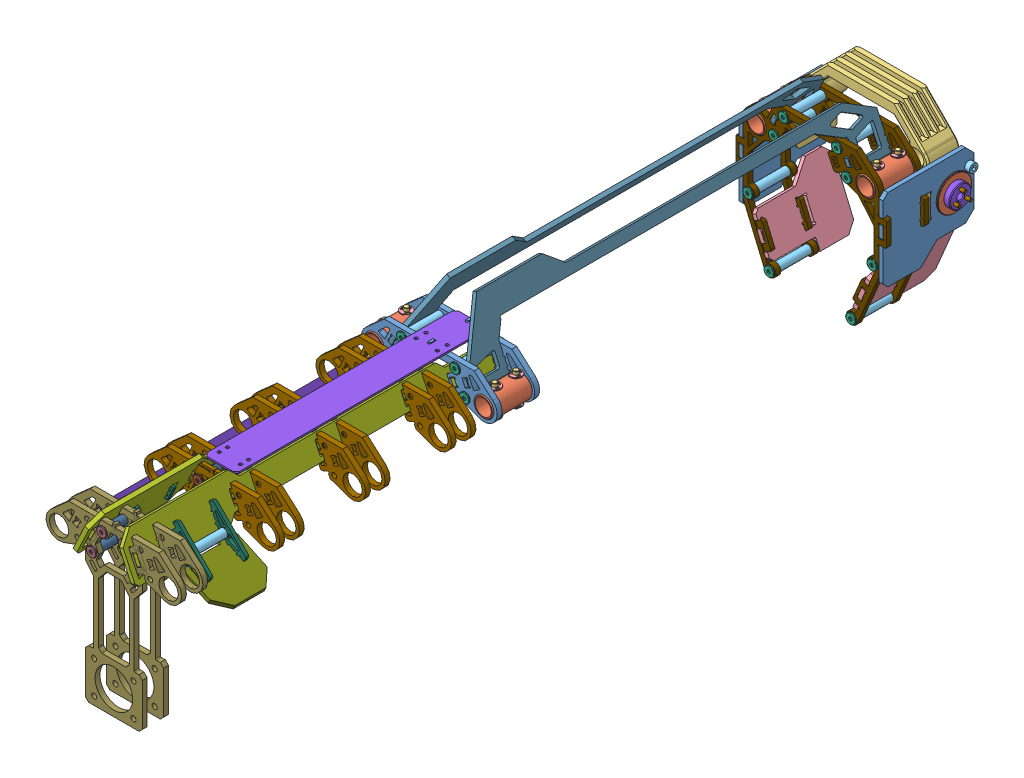
SolidWorks assembly 弹轮后支撑装配, configuration 默认. Lengths in mm.
Overall size (130 173.61 489.15).
144 component instances, 27 part files, 139 mates.
Components (placement in the parent):
- 弹轮后支撑-轨道连接板_3mm-1: 弹轮后支撑-轨道连接板_3mm [默认] at (0 0 -11.5) size (83 25.5 3)
- 碳管垫套_装填用_直径10mm-1: 碳管垫套_装填用_直径10mm [默认] at (33.5 0 0) x (0 1 0) z (0 0 1) size (14 14 27)
- 弹轮后支撑-轨道连接板_3mm-2: 弹轮后支撑-轨道连接板_3mm [默认] at (0 0 11.5) size (83 25.5 3)
- 碳管垫套_装填用_直径10mm-2: 碳管垫套_装填用_直径10mm [默认] at (-33.5 0 0) x (0 -1 0) z (0 0 1) size (14 14 27)
- M3×20卡簧销（工作长度15）-1: M3×20卡簧销（工作长度15） [默认] at (-33.5 0 6.5) x (0 -1 0) z (0.546944 0 -0.837169) size (20 3 3)
- M3×20卡簧销（工作长度15）-2: M3×20卡簧销（工作长度15） [默认] at (-33.5 0 -6.5) x (0 -1 0) z (0.546944 0 -0.837169) size (20 3 3)
- M3卡簧-1: M3卡簧 [默认] at (-33.5 8.1 6.5) x (-0.546944 0 0.837169) z (0 -1 0) size (7 6.39 0.6)
- M3卡簧-2: M3卡簧 [默认] at (-33.5 -7.5 -6.5) x (-0.546944 0 0.837169) z (0 -1 0) size (7 6.39 0.6)
- M3卡簧-3: M3卡簧 [默认] at (-33.5 8.1 -6.5) x (-0.546944 0 0.837169) z (0 -1 0) size (7 6.39 0.6)
- M3卡簧-4: M3卡簧 [默认] at (-33.5 -7.5 6.5) x (-0.546944 0 0.837169) z (0 -1 0) size (7 6.39 0.6)
- M3卡簧-5: M3卡簧 [默认] at (33.5 7.5 6.5) x (0.546944 0 0.837169) z (0 1 0) size (7 6.39 0.6)
- M3×20卡簧销（工作长度15）-3: M3×20卡簧销（工作长度15） [默认] at (33.5 0 6.5) x (0 -1 0) z (0.546944 0 0.837169) size (20 3 3)
- M3卡簧-6: M3卡簧 [默认] at (33.5 7.5 -6.5) x (0.546944 0 0.837169) z (0 1 0) size (7 6.39 0.6)
- M3×20卡簧销（工作长度15）-4: M3×20卡簧销（工作长度15） [默认] at (33.5 0 -6.5) x (0 -1 0) z (0.546944 0 0.837169) size (20 3 3)
- M3卡簧-7: M3卡簧 [默认] at (33.5 -8.1 -6.5) x (0.546944 0 0.837169) z (0 1 0) size (7 6.39 0.6)
- M3卡簧-8: M3卡簧 [默认] at (33.5 -8.1 6.5) x (0.546944 0 0.837169) z (0 1 0) size (7 6.39 0.6)
- M3×Φ5×20-1: M3×Φ5×20 [默认] at (-22.2445 -0.6154 0) size (5 5 20)
- M3×Φ5×20-2: M3×Φ5×20 [默认] at (-16.3278 12.0729 0) x (0.998279 0.058649 0) z (0 0 1) size (5 5 20)
- M3×8扁头螺丝-1: M3×8扁头螺丝 [默认] at (-16.3278 12.0729 13.5) size (6 6 9)
- M3×8扁头螺丝-2: M3×8扁头螺丝 [默认] at (-22.2445 -0.6154 13.5) size (6 6 9)
- M3×Φ5×20-3: M3×Φ5×20 [默认] at (16.3278 12.0729 0) x (-0.998279 0.058649 0) z (0 0 -1) size (5 5 20)
- M3×Φ5×20-4: M3×Φ5×20 [默认] at (22.2445 -0.6154 0) x (-1 0 0) z (0 0 -1) size (5 5 20)
- M3×8扁头螺丝-3: M3×8扁头螺丝 [默认] at (16.3278 12.0729 13.5) size (6 6 9)
- M3×8扁头螺丝-4: M3×8扁头螺丝 [默认] at (22.2445 -0.6154 13.5) size (6 6 9)
- M3×8扁头螺丝-5: M3×8扁头螺丝 [默认] at (-16.3278 12.0729 -13.5) x (0.592462 0.805599 0) z (0 0 -1) size (6 6 9)
- M3×8扁头螺丝-6: M3×8扁头螺丝 [默认] at (-22.2445 -0.6154 -13.5) x (0.639071 0.769148 0) z (0 0 -1) size (6 6 9)
- M3×8扁头螺丝-7: M3×8扁头螺丝 [默认] at (16.3278 12.0729 -13.5) x (0.592462 -0.805599 0) z (0 0 -1) size (6 6 9)
- M3×8扁头螺丝-8: M3×8扁头螺丝 [默认] at (22.2445 -0.6154 -13.5) x (0.639071 -0.769148 0) z (0 0 -1) size (6 6 9)
- 弹轮后支撑梁板_2.5mm-1: 弹轮后支撑梁板_2.5mm [默认] at (-14.9812 3.7213 96.4) x (0 0 1) z (-0.906308 0.422618 0) size (231 26 2.5)
- 弹轮后固定装饰板_1mm-1: 弹轮后固定装饰板_1mm [默认] at (0 16.5 64) x (0 0 1) z (0 -1 0) size (154 20 1)
- 弹轮后支撑梁板加强板_2mm-1: 弹轮后支撑梁板加强板_2mm [默认] at (0 -1.1831 27.4) size (83 25.5 3)
- 弹轮后支撑梁板加强板_2mm-2: 弹轮后支撑梁板加强板_2mm [默认] at (0 -1.1831 39.4) size (83 25.5 3)
- M3×Φ5×10-1: M3×Φ5×10 [默认] at (8.4109 6.572 33.4) size (5 5 10)
- M3×5扁头螺丝-1: M3×5扁头螺丝 [默认] at (8.4109 6.572 25.9) x (0.791441 0.611246 0) z (0 0 -1) size (6 6 6)
- M3×5扁头螺丝-2: M3×5扁头螺丝 [默认] at (8.4109 6.572 40.9) size (6 6 6)
- M3×Φ5×10-2: M3×Φ5×10 [默认] at (-8.4109 6.572 33.4) x (-1 0 0) z (0 0 -1) size (5 5 10)
- M3×5扁头螺丝-3: M3×5扁头螺丝 [默认] at (-8.4109 6.572 25.9) x (0.791441 -0.611246 0) z (0 0 -1) size (6 6 6)
- M3×5扁头螺丝-4: M3×5扁头螺丝 [默认] at (-8.4109 6.572 40.9) size (6 6 6)
- 弹轮后支撑梁板加强板_2mm-3: 弹轮后支撑梁板加强板_2mm [默认] at (0 -1.1831 91.9) size (83 25.5 3)
- 弹轮后支撑梁板加强板_2mm-4: 弹轮后支撑梁板加强板_2mm [默认] at (0 -1.1831 144.4) size (83 25.5 3)
- 弹轮后支撑梁板加强板_2mm-5: 弹轮后支撑梁板加强板_2mm [默认] at (0 -1.1831 79.9) size (83 25.5 3)
- 弹轮后支撑梁板加强板_2mm-6: 弹轮后支撑梁板加强板_2mm [默认] at (0 -1.1831 132.4) size (83 25.5 3)
- M3×5扁头螺丝-5: M3×5扁头螺丝 [默认] at (-8.4109 6.572 78.4) x (0.791441 -0.611246 0) z (0 0 -1) size (6 6 6)
- M3×5扁头螺丝-6: M3×5扁头螺丝 [默认] at (-8.4109 6.572 130.9) x (0.791441 -0.611246 0) z (0 0 -1) size (6 6 6)
- M3×5扁头螺丝-7: M3×5扁头螺丝 [默认] at (-8.4109 6.572 93.4) size (6 6 6)
- M3×5扁头螺丝-8: M3×5扁头螺丝 [默认] at (-8.4109 6.572 145.9) size (6 6 6)
- M3×Φ5×10-3: M3×Φ5×10 [默认] at (-8.4109 6.572 85.9) x (-1 0 0) z (0 0 -1) size (5 5 10)
- M3×Φ5×10-4: M3×Φ5×10 [默认] at (-8.4109 6.572 138.4) x (-1 0 0) z (0 0 -1) size (5 5 10)
- M3×5扁头螺丝-9: M3×5扁头螺丝 [默认] at (8.4109 6.572 93.4) size (6 6 6)
- M3×5扁头螺丝-10: M3×5扁头螺丝 [默认] at (8.4109 6.572 145.9) size (6 6 6)
- M3×5扁头螺丝-11: M3×5扁头螺丝 [默认] at (8.4109 6.572 78.4) x (0.791441 0.611246 0) z (0 0 -1) size (6 6 6)
- M3×5扁头螺丝-12: M3×5扁头螺丝 [默认] at (8.4109 6.572 130.9) x (0.791441 0.611246 0) z (0 0 -1) size (6 6 6)
- M3×Φ5×10-5: M3×Φ5×10 [默认] at (8.4109 6.572 85.9) size (5 5 10)
- M3×Φ5×10-6: M3×Φ5×10 [默认] at (8.4109 6.572 138.4) size (5 5 10)
- 弹轮后支撑托垫板_3mm-1: 弹轮后支撑托垫板_3mm [默认] at (0 0 191.4) size (83 102 3)
- 弹轮后支撑托垫板_3mm-2: 弹轮后支撑托垫板_3mm [默认] at (0 0 204.4) size (83 102 3)
- M3×6扁头螺丝-1: M3×6扁头螺丝 [默认] at (-13.0006 -3.2708 206.4) size (6 6 7)
- M3×6扁头螺丝-2: M3×6扁头螺丝 [默认] at (-6.6614 10.3238 206.4) size (6 6 7)
- M3×6扁头螺丝-3: M3×6扁头螺丝 [默认] at (-6.6614 10.3238 189.4) x (-0.778141 0.62809 0) z (0 0 -1) size (6 6 7)
- M3×6扁头螺丝-4: M3×6扁头螺丝 [默认] at (-13.0006 -3.2708 189.4) x (-0.791739 0.61086 0) z (0 0 -1) size (6 6 7)
- M3×6扁头螺丝-5: M3×6扁头螺丝 [默认] at (13.0006 -3.2708 189.4) x (-0.791739 -0.61086 0) z (0 0 -1) size (6 6 7)
- M3×6扁头螺丝-6: M3×6扁头螺丝 [默认] at (13.0006 -3.2708 206.4) size (6 6 7)
- M3×6扁头螺丝-7: M3×6扁头螺丝 [默认] at (6.6614 10.3238 206.4) size (6 6 7)
- M3×6扁头螺丝-8: M3×6扁头螺丝 [默认] at (6.6614 10.3238 189.4) x (-0.778141 -0.62809 0) z (0 0 -1) size (6 6 7)
- 弹轮后支撑梁板_2.5mm-3: 弹轮后支撑梁板_2.5mm [默认] at (14.9812 3.7213 96.4) x (0 0 1) z (-0.906308 -0.422618 0) size (231 26 2.5)
- M3×Φ5×10-11: M3×Φ5×10 [默认] at (-6.6614 10.3238 197.9) x (0.722592 0.691274 0) z (0 0 1) size (5 5 10)
- M3×Φ5×10-12: M3×Φ5×10 [默认] at (-13.0006 -3.2708 197.9) x (0.999082 -0.042836 0) z (0 0 1) size (5 5 10)
- M3×Φ5×10-13: M3×Φ5×10 [默认] at (6.6614 10.3238 197.9) x (-0.722592 0.691274 0) z (0 0 -1) size (5 5 10)
- M3×Φ5×10-14: M3×Φ5×10 [默认] at (13.0006 -3.2708 197.9) x (-0.999082 -0.042836 0) z (0 0 -1) size (5 5 10)
- M3卡簧-9: M3卡簧 [默认] at (33.5 -8.1 -240) x (0.546944 0 0.837169) z (0 1 0) size (7 6.39 0.6)
- M3卡簧-10: M3卡簧 [默认] at (33.5 -8.1 -227) x (0.546944 0 0.837169) z (0 1 0) size (7 6.39 0.6)
- M3×Φ5×20-5: M3×Φ5×20 [默认] at (22.2445 -0.6154 -233.5) x (-1 0 0) z (0 0 -1) size (5 5 20)
- M3卡簧-11: M3卡簧 [默认] at (33.5 7.5 -227) x (0.546944 0 0.837169) z (0 1 0) size (7 6.39 0.6)
- M3卡簧-12: M3卡簧 [默认] at (33.5 7.5 -240) x (0.546944 0 0.837169) z (0 1 0) size (7 6.39 0.6)
- M3×20卡簧销（工作长度15）-5: M3×20卡簧销（工作长度15） [默认] at (33.5 0 -240) x (0 -1 0) z (0.546944 0 0.837169) size (20 3 3)
- M3×20卡簧销（工作长度15）-6: M3×20卡簧销（工作长度15） [默认] at (33.5 0 -227) x (0 -1 0) z (0.546944 0 0.837169) size (20 3 3)
- 碳管垫套_装填用_直径10mm-3: 碳管垫套_装填用_直径10mm [默认] at (33.5 0 -233.5) x (0 1 0) z (0 0 1) size (14 14 27)
- M3×8扁头螺丝-9: M3×8扁头螺丝 [默认] at (22.2445 -0.6154 -220) size (6 6 9)
- M3×8扁头螺丝-10: M3×8扁头螺丝 [默认] at (16.3278 12.0729 -220) size (6 6 9)
- M3×Φ5×20-6: M3×Φ5×20 [默认] at (16.3278 12.0729 -233.5) x (-0.998279 0.058649 0) z (0 0 -1) size (5 5 20)
- M3×8扁头螺丝-11: M3×8扁头螺丝 [默认] at (16.3278 12.0729 -247) x (0.592462 -0.805599 0) z (0 0 -1) size (6 6 9)
- M3×8扁头螺丝-12: M3×8扁头螺丝 [默认] at (22.2445 -0.6154 -247) x (0.639071 -0.769148 0) z (0 0 -1) size (6 6 9)
- M3×8扁头螺丝-13: M3×8扁头螺丝 [默认] at (-22.2445 -0.6154 -247) x (0.639071 0.769148 0) z (0 0 -1) size (6 6 9)
- M3×8扁头螺丝-14: M3×8扁头螺丝 [默认] at (-16.3278 12.0729 -247) x (0.592462 0.805599 0) z (0 0 -1) size (6 6 9)
- M3×8扁头螺丝-15: M3×8扁头螺丝 [默认] at (-22.2445 -0.6154 -220) size (6 6 9)
- M3×8扁头螺丝-16: M3×8扁头螺丝 [默认] at (-16.3278 12.0729 -220) size (6 6 9)
- M3×Φ5×20-7: M3×Φ5×20 [默认] at (-22.2445 -0.6154 -233.5) size (5 5 20)
- M3×Φ5×20-8: M3×Φ5×20 [默认] at (-16.3278 12.0729 -233.5) x (0.998279 0.058649 0) z (0 0 1) size (5 5 20)
- M3卡簧-13: M3卡簧 [默认] at (-33.5 8.1 -227) x (-0.546944 0 0.837169) z (0 -1 0) size (7 6.39 0.6)
- M3×20卡簧销（工作长度15）-7: M3×20卡簧销（工作长度15） [默认] at (-33.5 0 -227) x (0 -1 0) z (0.546944 0 -0.837169) size (20 3 3)
- M3卡簧-14: M3卡簧 [默认] at (-33.5 -7.5 -227) x (-0.546944 0 0.837169) z (0 -1 0) size (7 6.39 0.6)
- M3卡簧-15: M3卡簧 [默认] at (-33.5 -7.5 -240) x (-0.546944 0 0.837169) z (0 -1 0) size (7 6.39 0.6)
- M3×20卡簧销（工作长度15）-8: M3×20卡簧销（工作长度15） [默认] at (-33.5 0 -240) x (0 -1 0) z (0.546944 0 -0.837169) size (20 3 3)
- M3卡簧-16: M3卡簧 [默认] at (-33.5 8.1 -240) x (-0.546944 0 0.837169) z (0 -1 0) size (7 6.39 0.6)
- 碳管垫套_装填用_直径10mm-4: 碳管垫套_装填用_直径10mm [默认] at (-33.5 0 -233.5) x (0 -1 0) z (0 0 1) size (14 14 27)
- 轨道上支撑梁板_2.5mm-1: 轨道上支撑梁板_2.5mm [默认] at (-25.0092 2.3288 -116.75) x (0 0 1) z (-0.906308 0.422618 0) size (260.5 40 2.5)
- 轨道上支撑梁板_2.5mm-3: 轨道上支撑梁板_2.5mm [默认] at (25.0092 2.3288 -116.75) x (0 0 1) z (-0.906308 -0.422618 0) size (260.5 40 2.5)
- 弹轮后支撑梁板装饰板支撑板_2mm-1: 弹轮后支撑梁板装饰板支撑板_2mm [默认] at (-21.1574 0.5327 158.9) x (0.906308 0.422618 0) z (0 0 1) size (28.49 16.46 2)
- 弹轮后支撑梁板装饰板支撑板_2mm-2: 弹轮后支撑梁板装饰板支撑板_2mm [默认] at (-21.1574 0.5327 180.9) x (0.906308 0.422618 0) z (0 0 1) size (28.49 16.46 2)
- M3×Φ5×20-9: M3×Φ5×20 [默认] at (-21.1574 0.5327 169.9) size (5 5 20)
- M3×6扁头螺丝-9: M3×6扁头螺丝 [默认] at (-21.1574 0.5327 157.4) x (-0.923728 -0.383049 0) z (0 0 -1) size (6 6 7)
- M3×6扁头螺丝-10: M3×6扁头螺丝 [默认] at (-21.1574 0.5327 182.4) size (6 6 7)
- M3×Φ5×20-10: M3×Φ5×20 [默认] at (21.1574 0.5327 169.9) x (-1 0 0) z (0 0 -1) size (5 5 20)
- 弹轮后支撑梁板装饰板支撑板_2mm-3: 弹轮后支撑梁板装饰板支撑板_2mm [默认] at (21.1574 0.5327 158.9) x (-0.906308 0.422618 0) z (0 0 -1) size (28.49 16.46 2)
- 弹轮后支撑梁板装饰板支撑板_2mm-4: 弹轮后支撑梁板装饰板支撑板_2mm [默认] at (21.1574 0.5327 180.9) x (-0.906308 0.422618 0) z (0 0 -1) size (28.49 16.46 2)
- M3×6扁头螺丝-11: M3×6扁头螺丝 [默认] at (21.1574 0.5327 182.4) size (6 6 7)
- M3×6扁头螺丝-12: M3×6扁头螺丝 [默认] at (21.1574 0.5327 157.4) x (-0.923728 0.383049 0) z (0 0 -1) size (6 6 7)
- 弹轮后固定装饰板2_2.5mm-4: 弹轮后固定装饰板2_2.5mm [默认] at (19.8144 -3.5304 169.9) x (0 0 -1) z (0.422618 0.906308 0) size (35 30 2.5)
- 弹轮后固定装饰板3_2.5mm-5: 弹轮后固定装饰板3_2.5mm [默认] at (-19.8144 -3.5304 100.7) x (0 0 -1) z (0.422618 -0.906308 0) size (173.4 30 2.5)
- 飞镖架前支撑-轨道连接板_3mm-1: 飞镖架前支撑-轨道连接板_3mm [默认] at (0 0 -245) x (-1 0 0) z (0 0 -1) size (92 93.5 3)
- 飞镖架前支撑-轨道连接板_3mm-2: 飞镖架前支撑-轨道连接板_3mm [默认] at (0 0 -222) x (-1 0 0) z (0 0 -1) size (92 93.5 3)
- 飞镖架前支撑轴承板_2.5mm-1: 飞镖架前支撑轴承板_2.5mm [默认] at (42.75 -19.5 -233.5) x (0 0 -1) z (1 0 0) size (55.53 50 2.5)
- M3×8扁头螺丝-17: M3×8扁头螺丝 [默认] at (38 -39 -220) size (6 6 9)
- M3×8扁头螺丝-18: M3×8扁头螺丝 [默认] at (38 -39 -247) x (-0.877487 0.479601 0) z (0 0 -1) size (6 6 9)
- M3×Φ5×20-11: M3×Φ5×20 [默认] at (38 -39 -233.5) size (5 5 20)
- 飞镖架前支撑轴承板_2.5mm-2: 飞镖架前支撑轴承板_2.5mm [默认] at (-42.75 -19.5 -233.5) x (0 0 -1) z (1 0 0) size (55.53 50 2.5)
- M3×8扁头螺丝-19: M3×8扁头螺丝 [默认] at (-38 -39 -247) x (-0.877487 -0.479601 0) z (0 0 -1) size (6 6 9)
- M3×Φ5×20-12: M3×Φ5×20 [默认] at (-38 -39 -233.5) x (-1 0 0) z (0 0 -1) size (5 5 20)
- M3×8扁头螺丝-20: M3×8扁头螺丝 [默认] at (-38 -39 -220) size (6 6 9)
- 法兰轴承10×19×5-1: 法兰轴承10×19×5 [默认] at (-45 -19.5 -263.5) x (0 -0.388043 -0.921641) z (1 0 0) size (21 21 5)
- 飞镖架前支撑轴承垫块-1: 飞镖架前支撑轴承垫块 [默认] at (0 0 -263.5) size (88 54.76 29.5)
- 法兰轴承10×19×5-2: 法兰轴承10×19×5 [默认] at (45 -19.5 -263.5) x (0 0.388043 0.921641) z (-1 0 0) size (21 21 5)
- 飞镖架前支撑装饰板_2.5mm-1: 飞镖架前支撑装饰板_2.5mm [默认] at (30.7414 -58.5129 -245.5) x (0 0 -1) z (-0.389823 -0.92089 0) size (50.02 2.5 35)
- 飞镖架前支撑装饰板_2.5mm-2: 飞镖架前支撑装饰板_2.5mm [默认] at (-30.7414 -58.5129 -245.5) x (0 0 -1) z (0.389823 -0.92089 0) size (50.02 2.5 35)
- M3×8扁头螺丝-21: M3×8扁头螺丝 [默认] at (25 -74 -220) x (-0.75335 0.65762 0) z (0 0 1) size (6 6 9)
- M3×8扁头螺丝-22: M3×8扁头螺丝 [默认] at (25 -74 -247) x (-0.440843 -0.897584 0) z (0 0 -1) size (6 6 9)
- M3×Φ5×20-13: M3×Φ5×20 [默认] at (25 -74 -233.5) size (5 5 20)
- M3×Φ5×20-14: M3×Φ5×20 [默认] at (-25 -74 -233.5) x (-1 0 0) z (0 0 -1) size (5 5 20)
- M3×8扁头螺丝-23: M3×8扁头螺丝 [默认] at (-25 -74 -247) x (-0.440843 0.897584 0) z (0 0 -1) size (6 6 9)
- M3×8扁头螺丝-24: M3×8扁头螺丝 [默认] at (-25 -74 -220) x (-0.75335 -0.65762 0) z (0 0 1) size (6 6 9)
- 内六角圆柱头螺钉M3×10-1: 内六角圆柱头螺钉M3×10 [默认] at (47 -9.9541 -273.0459) x (-1 0 0) z (0 0.999499 -0.031662) size (13 5.2 5.2)
- M3防松-2: M3防松 [默认] at (38.1 -9.9541 -273.0459) x (0 -0.142302 -0.989823) z (0 0.989823 -0.142302) size (6.24 3.5 5.4)
- 内六角圆柱头螺钉M3×10-3: 内六角圆柱头螺钉M3×10 [默认] at (-47 -9.9541 -273.0459) x (1 0 0) z (0 -0.999499 0.031662) size (13 5.2 5.2)
- M3防松-3: M3防松 [默认] at (-38.1 -9.9541 -273.0459) x (0 -0.142302 -0.989823) z (0 -0.989823 0.142302) size (6.24 3.5 5.4)
- 飞镖架前支撑轴系垫块1-1: 飞镖架前支撑轴系垫块1 [默认] at (-40 -19.5 -263.5) x (0 0.853684 -0.520791) z (1 0 0) size (13.5 13.5 5.06)
- 飞镖架前支撑轴系垫块2-1: 飞镖架前支撑轴系垫块2 [默认] at (-45 -19.5 -263.5) x (0 0.024176 0.999708) z (-1 0 0) size (13.5 13.5 6.46)
- M2×6销钉-1: M2×6销钉 [默认] at (-48.5 -21.4157 -259.9886) x (0 -0.583122 0.812385) z (-1 0 0) size (2 2 6)
- M2×6销钉-2: M2×6销钉 [默认] at (-48.5 -15.5012 -263.5967) x (0 -0.912857 0.408278) z (-1 0 0) size (2 2 6)
- M2×6销钉-3: M2×6销钉 [默认] at (-48.5 -21.5832 -266.9147) x (0 -0.993447 0.114292) z (-1 0 0) size (2 2 6)
- 飞镖架前支撑轴系垫块2-2: 飞镖架前支撑轴系垫块2 [默认] at (45 -19.5 -263.5) x (0 -0.024176 -0.999708) z (1 0 0) size (13.5 13.5 6.46)
- M2×6销钉-4: M2×6销钉 [默认] at (48.5 -15.5012 -263.5967) x (0 -0.912857 0.408278) z (-1 0 0) size (2 2 6)
- M2×6销钉-5: M2×6销钉 [默认] at (48.5 -21.4157 -259.9886) x (0 -0.583122 0.812385) z (-1 0 0) size (2 2 6)
- M2×6销钉-6: M2×6销钉 [默认] at (48.5 -21.5832 -266.9147) x (0 -0.993447 0.114292) z (-1 0 0) size (2 2 6)
- 飞镖架前支撑轴系垫块1-2: 飞镖架前支撑轴系垫块1 [默认] at (40 -19.5 -263.5) x (0 -0.853684 0.520791) z (-1 0 0) size (13.5 13.5 5.06)
Mates (geometry in assembly coordinates):
- 重合2: coincident aligned: plane of 弹轮后支撑-轨道连接板_3mm-1 through (0 0 -11.5) normal (0 1 0)
- 重合3: coincident aligned: plane of 弹轮后支撑-轨道连接板_3mm-1 through (0 0 -11.5) normal (1 0 0)
- 同心1: concentric anti-aligned: cylinder of 弹轮后支撑-轨道连接板_3mm-1 through (33.5 0 -10) axis (0 0 -1) radius 6; cylinder of 碳管垫套_装填用_直径10mm-1 through (33.5 0 13.5) axis (0 0 1) radius 6.05
- 重合4: coincident anti-aligned: plane of 弹轮后支撑-轨道连接板_3mm-1 through (-33.5 0 -10) normal (0 0 1); plane of 碳管垫套_装填用_直径10mm-1 through (27.45 0 -10) normal (0 0 -1)
- 同心2: concentric anti-aligned: cylinder of 碳管垫套_装填用_直径10mm-1 through (33.5 0 13.5) axis (0 0 1) radius 6.05; cylinder of 弹轮后支撑-轨道连接板_3mm-2 through (33.5 0 13) axis (0 0 -1) radius 6
- 重合5: coincident anti-aligned: plane of 碳管垫套_装填用_直径10mm-1 through (26.5 0 10) normal (0 0 1); plane of 弹轮后支撑-轨道连接板_3mm-2 through (-33.5 0 10) normal (0 0 -1)
- 同心3: concentric aligned: cylinder of 弹轮后支撑-轨道连接板_3mm-1 through (-33.5 0 -10) axis (0 0 -1) radius 6; cylinder of 弹轮后支撑-轨道连接板_3mm-2 through (-33.5 0 13) axis (0 0 -1) radius 6
- 同心4: concentric anti-aligned: cylinder of 弹轮后支撑-轨道连接板_3mm-2 through (-33.5 0 13) axis (0 0 -1) radius 6; cylinder of 碳管垫套_装填用_直径10mm-2 through (-33.5 0 13.5) axis (0 0 1) radius 6.05
- 重合6: coincident anti-aligned: plane of 弹轮后支撑-轨道连接板_3mm-2 through (-33.5 0 10) normal (0 0 -1); plane of 碳管垫套_装填用_直径10mm-2 through (-26.5 0 10) normal (0 0 1)
- 对称2: symmetric aligned: plane of 弹轮后支撑-轨道连接板_3mm-1 through (-33.5 0 -10) normal (0 0 1); plane of 弹轮后支撑-轨道连接板_3mm-2 through (-33.5 0 10) normal (0 0 -1)
- 同心5: concentric anti-aligned: cylinder of M3×20卡簧销（工作长度15）-1 through (-33.5 8.1 6.5) axis (0 -1 0) radius 1.2; cylinder of M3卡簧-1 through (-33.5 7.5 6.5) axis (0 1 0) radius 1.4
- 重合7: coincident anti-aligned: plane of M3×20卡簧销（工作长度15）-1 through (-33.5 8.1 6.5) normal (0 -1 0); plane of M3卡簧-1 through (-33.5 8.1 6.5) normal (0 1 0)
- 同心6: concentric aligned: cylinder of M3×20卡簧销（工作长度15）-1 through (-33.5 -8.1 6.5) axis (0 1 0) radius 1.2; cylinder of M3卡簧-4 through (-33.5 -8.1 6.5) axis (0 1 0) radius 1.4
- 重合8: coincident anti-aligned: plane of M3×20卡簧销（工作长度15）-1 through (-33.5 -8.1 6.5) normal (0 1 0); plane of M3卡簧-4 through (-33.5 -8.1 6.5) normal (0 -1 0)
- 同心7: concentric anti-aligned: cylinder of 碳管垫套_装填用_直径10mm-2 through (-33.5 7 6.5) axis (0 -1 0) radius 1.45; cylinder of M3×20卡簧销（工作长度15）-1 through (-33.5 -10 6.5) axis (0 1 0) radius 1.5
- 重合9: coincident aligned: plane of 碳管垫套_装填用_直径10mm-2 through (-33.5 0 0) normal (0 -1 0); plane of M3×20卡簧销（工作长度15）-1 through (-33.5 0 6.5) normal (0 -1 0)
- 同心8: concentric anti-aligned: cylinder of M3×20卡簧销（工作长度15）-2 through (-33.5 8.1 -6.5) axis (0 -1 0) radius 1.2; cylinder of M3卡簧-3 through (-33.5 7.5 -6.5) axis (0 1 0) radius 1.4
- 重合10: coincident anti-aligned: plane of M3×20卡簧销（工作长度15）-2 through (-33.5 8.1 -6.5) normal (0 -1 0); plane of M3卡簧-3 through (-33.5 8.1 -6.5) normal (0 1 0)
- 重合11: coincident anti-aligned: plane of M3×20卡簧销（工作长度15）-2 through (-33.5 -8.1 -6.5) normal (0 1 0); plane of M3卡簧-2 through (-33.5 -8.1 -6.5) normal (0 -1 0)
- 同心9: concentric aligned: cylinder of M3×20卡簧销（工作长度15）-2 through (-33.5 -8.1 -6.5) axis (0 1 0) radius 1.2; cylinder of M3卡簧-2 through (-33.5 -8.1 -6.5) axis (0 1 0) radius 1.4
- 同心10: concentric anti-aligned: cylinder of 碳管垫套_装填用_直径10mm-2 through (-33.5 7 -6.5) axis (0 -1 0) radius 1.45; cylinder of M3×20卡簧销（工作长度15）-2 through (-33.5 -10 -6.5) axis (0 1 0) radius 1.5
- 重合12: coincident aligned: plane of 碳管垫套_装填用_直径10mm-2 through (-33.5 0 0) normal (0 -1 0); plane of M3×20卡簧销（工作长度15）-2 through (-33.5 0 -6.5) normal (0 -1 0)
- 同心11: concentric anti-aligned: cylinder of 弹轮后支撑-轨道连接板_3mm-2 through (-16.3278 12.0729 10) axis (0 0 1) radius 1.55; cylinder of M3×Φ5×20-2 through (-16.3278 12.0729 10) axis (0 0 -1) radius 1.5
- 同心12: concentric anti-aligned: cylinder of 弹轮后支撑-轨道连接板_3mm-2 through (-22.2445 -0.6154 10) axis (0 0 1) radius 1.55; cylinder of M3×Φ5×20-1 through (-22.2445 -0.6154 10) axis (0 0 -1) radius 1.5
- 重合13: coincident anti-aligned: plane of 弹轮后支撑-轨道连接板_3mm-2 through (-33.5 0 10) normal (0 0 -1); plane of M3×Φ5×20-1 through (-22.2445 -0.6154 10) normal (0 0 1)
- 重合14: coincident anti-aligned: plane of 弹轮后支撑-轨道连接板_3mm-2 through (-33.5 0 10) normal (0 0 -1); plane of M3×Φ5×20-2 through (-16.3278 12.0729 10) normal (0 0 1)
- 同心13: concentric aligned: cylinder of 弹轮后支撑-轨道连接板_3mm-2 through (-16.3278 12.0729 10) axis (0 0 1) radius 1.55; cylinder of M3×8扁头螺丝-1 through (-16.3278 12.0729 5) axis (0 0 1) radius 1.5
- 同心14: concentric aligned: cylinder of 弹轮后支撑-轨道连接板_3mm-2 through (-22.2445 -0.6154 10) axis (0 0 1) radius 1.55; cylinder of M3×8扁头螺丝-2 through (-22.2445 -0.6154 5) axis (0 0 1) radius 1.5
- 重合15: coincident anti-aligned: plane of 弹轮后支撑-轨道连接板_3mm-2 through (-33.5 0 13) normal (0 0 1); plane of M3×8扁头螺丝-1 through (-16.3278 12.0729 13) normal (0 0 -1)
- 重合16: coincident anti-aligned: plane of 弹轮后支撑-轨道连接板_3mm-2 through (-33.5 0 13) normal (0 0 1); plane of M3×8扁头螺丝-2 through (-22.2445 -0.6154 13) normal (0 0 -1)
- 同心15: concentric anti-aligned: cylinder of 弹轮后支撑-轨道连接板_3mm-1 through (-16.3278 12.0729 -13) axis (0 0 1) radius 1.55; cylinder of M3×8扁头螺丝-5 through (-16.3278 12.0729 -5) axis (0 0 -1) radius 1.5
- 同心16: concentric anti-aligned: cylinder of 弹轮后支撑-轨道连接板_3mm-1 through (-22.2445 -0.6154 -13) axis (0 0 1) radius 1.55; cylinder of M3×8扁头螺丝-6 through (-22.2445 -0.6154 -5) axis (0 0 -1) radius 1.5
- 重合17: coincident anti-aligned: plane of 弹轮后支撑-轨道连接板_3mm-1 through (-33.5 0 -13) normal (0 0 -1); plane of M3×8扁头螺丝-5 through (-16.3278 12.0729 -13) normal (0 0 1)
- 重合18: coincident anti-aligned: plane of 弹轮后支撑-轨道连接板_3mm-1 through (-33.5 0 -13) normal (0 0 -1); plane of M3×8扁头螺丝-6 through (-22.2445 -0.6154 -13) normal (0 0 1)
- 重合19: coincident anti-aligned: plane of 弹轮后支撑-轨道连接板_3mm-2 through (-12.5 12 13) normal (0.906308 -0.422618 0); plane of 弹轮后支撑梁板_2.5mm-1 through (-16.1141 4.2496 96.4) normal (-0.906308 0.422618 0)
- 宽度1: width anti-aligned: plane of 弹轮后支撑梁板_2.5mm-1 through (-15.0575 6.5153 10.025) normal (0 0 1); plane of 弹轮后支撑梁板_2.5mm-1 through (-15.0575 6.5153 -10.025) normal (0 0 -1); plane of 弹轮后支撑-轨道连接板_3mm-2 through (-33.5 0 10) normal (0 0 -1); plane of 弹轮后支撑-轨道连接板_3mm-1 through (-33.5 0 -10) normal (0 0 1)
- 宽度2: width aligned: plane of 弹轮后支撑梁板_2.5mm-1 through (-15.0575 6.5153 10.025) normal (0.422618 0.906308 0); plane of 弹轮后支撑梁板_2.5mm-1 through (-17.1706 1.9838 13.025) normal (-0.422618 -0.906308 0); plane of 弹轮后支撑-轨道连接板_3mm-2 through (-14.9049 0.9272 10) normal (0.422618 0.906308 0); plane of 弹轮后支撑-轨道连接板_3mm-2 through (-15.0575 6.5153 10) normal (-0.422618 -0.906308 0)
- 重合20: coincident anti-aligned: plane of 弹轮后支撑-轨道连接板_3mm-1 through (-27.5 16 -10) normal (0 1 0); plane of 弹轮后固定装饰板_1mm-1 through (0 16 64) normal (0 -1 0)
- 重合21: coincident anti-aligned: plane of 弹轮后固定装饰板_1mm-1 through (0 16.5 64) normal (-1 0 0)
- 重合25: coincident anti-aligned: plane of 弹轮后支撑梁板_2.5mm-1 through (-13.8483 3.193 96.4) normal (0.906308 -0.422618 0); plane of 弹轮后支撑梁板加强板_2mm-1 through (-8.6246 14.3953 28.4) normal (-0.906308 0.422618 0)
- 重合27: coincident anti-aligned: plane of 弹轮后支撑梁板_2.5mm-1 through (-13.8483 3.193 96.4) normal (0.906308 -0.422618 0); plane of 弹轮后支撑梁板加强板_2mm-2 through (-8.6246 14.3953 40.4) normal (-0.906308 0.422618 0)
- 同心17: concentric anti-aligned: cylinder of 弹轮后支撑梁板加强板_2mm-2 through (8.4109 6.572 37.9) axis (0 0 1) radius 1.55; cylinder of M3×Φ5×10-1 through (8.4109 6.572 38.4) axis (0 0 -1) radius 1.5
- 重合29: coincident anti-aligned: plane of 弹轮后支撑梁板加强板_2mm-2 through (0 -1.1831 38.4) normal (0 0 -1); plane of M3×Φ5×10-1 through (8.4109 6.572 38.4) normal (0 0 1)
- 同心18: concentric aligned: cylinder of 弹轮后支撑梁板加强板_2mm-2 through (8.4109 6.572 37.9) axis (0 0 1) radius 1.55; cylinder of M3×5扁头螺丝-2 through (8.4109 6.572 35.4) axis (0 0 1) radius 1.5
- 重合30: coincident anti-aligned: plane of 弹轮后支撑梁板加强板_2mm-2 through (0 -1.1831 40.4) normal (0 0 1); plane of M3×5扁头螺丝-2 through (8.4109 6.572 40.4) normal (0 0 -1)
- 同心19: concentric anti-aligned: cylinder of 弹轮后支撑梁板加强板_2mm-1 through (8.4109 6.572 25.9) axis (0 0 1) radius 1.55; cylinder of M3×5扁头螺丝-1 through (8.4109 6.572 31.4) axis (0 0 -1) radius 1.5
- 重合31: coincident anti-aligned: plane of 弹轮后支撑梁板加强板_2mm-1 through (0 -1.1831 26.4) normal (0 0 -1); plane of M3×5扁头螺丝-1 through (8.4109 6.572 26.4) normal (0 0 1)
- 重合32: coincident anti-aligned: plane of 弹轮后支撑梁板加强板_2mm-1 through (0 -1.1831 28.4) normal (0 0 1); plane of M3×Φ5×10-1 through (8.4109 6.572 28.4) normal (0 0 -1)
- 重合33: coincident anti-aligned: plane of 弹轮后支撑梁板_2.5mm-1 through (-13.8483 3.193 96.4) normal (0.906308 -0.422618 0); plane of 弹轮后支撑托垫板_3mm-1 through (-8.5656 14.5219 192.9) normal (-0.906308 0.422618 0)
- 重合34: coincident anti-aligned: plane of 弹轮后支撑梁板_2.5mm-1 through (-13.8483 3.193 96.4) normal (0.906308 -0.422618 0); plane of 弹轮后支撑托垫板_3mm-2 through (-8.5656 14.5219 205.9) normal (-0.906308 0.422618 0)
- 宽度4: width anti-aligned: plane of 弹轮后支撑托垫板_3mm-1 through (0 0 192.9) normal (0 0 1); plane of 弹轮后支撑梁板_2.5mm-1 through (0 0 202.9) normal (0 0 -1); plane of 弹轮后支撑托垫板_3mm-2 through (-11.5239 8.1777 192.875) normal (0 0 -1); plane of 弹轮后支撑梁板_2.5mm-1 through (-11.5239 8.1777 202.925) normal (0 0 1)
- 重合37: coincident anti-aligned: plane of 弹轮后支撑托垫板_3mm-1 through (0 0 189.9) normal (0 0 -1); plane of M3×6扁头螺丝-4 through (-13.0006 -3.2708 189.9) normal (0 0 1)
- 重合38: coincident anti-aligned: plane of 弹轮后支撑托垫板_3mm-1 through (0 0 189.9) normal (0 0 -1); plane of M3×6扁头螺丝-3 through (-6.6614 10.3238 189.9) normal (0 0 1)
- 同心20: concentric anti-aligned: cylinder of 弹轮后支撑托垫板_3mm-1 through (-6.6614 10.3238 189.9) axis (0 0 1) radius 1.55; cylinder of M3×6扁头螺丝-3 through (-6.6614 10.3238 195.9) axis (0 0 -1) radius 1.5
- 同心21: concentric anti-aligned: cylinder of 弹轮后支撑托垫板_3mm-1 through (-13.0006 -3.2708 189.9) axis (0 0 1) radius 1.55; cylinder of M3×6扁头螺丝-4 through (-13.0006 -3.2708 195.9) axis (0 0 -1) radius 1.5
- 重合39: coincident anti-aligned: plane of 弹轮后支撑托垫板_3mm-2 through (0 0 205.9) normal (0 0 1); plane of M3×6扁头螺丝-2 through (-6.6614 10.3238 205.9) normal (0 0 -1)
- 重合40: coincident anti-aligned: plane of 弹轮后支撑托垫板_3mm-2 through (0 0 205.9) normal (0 0 1); plane of M3×6扁头螺丝-1 through (-13.0006 -3.2708 205.9) normal (0 0 -1)
- 同心22: concentric aligned: cylinder of 弹轮后支撑托垫板_3mm-2 through (-6.6614 10.3238 202.9) axis (0 0 1) radius 1.55; cylinder of M3×6扁头螺丝-2 through (-6.6614 10.3238 199.9) axis (0 0 1) radius 1.5
- 同心23: concentric aligned: cylinder of 弹轮后支撑托垫板_3mm-2 through (-13.0006 -3.2708 202.9) axis (0 0 1) radius 1.55; cylinder of M3×6扁头螺丝-1 through (-13.0006 -3.2708 199.9) axis (0 0 1) radius 1.5
- 同心29: concentric anti-aligned: cylinder of M3×6扁头螺丝-1 through (-13.0006 -3.2708 199.9) axis (0 0 1) radius 1.5; cylinder of M3×Φ5×10-12 through (-13.0006 -3.2708 202.9) axis (0 0 -1) radius 1.5
- 同心30: concentric anti-aligned: cylinder of M3×6扁头螺丝-2 through (-6.6614 10.3238 199.9) axis (0 0 1) radius 1.5; cylinder of M3×Φ5×10-11 through (-6.6614 10.3238 202.9) axis (0 0 -1) radius 1.5
- 重合48: coincident anti-aligned: plane of 弹轮后支撑托垫板_3mm-2 through (0 0 202.9) normal (0 0 -1); plane of M3×Φ5×10-12 through (-13.0006 -3.2708 202.9) normal (0 0 1)
- 重合49: coincident anti-aligned: plane of 弹轮后支撑托垫板_3mm-2 through (0 0 202.9) normal (0 0 -1); plane of M3×Φ5×10-11 through (-6.6614 10.3238 202.9) normal (0 0 1)
- 重合50: coincident anti-aligned: plane of 弹轮后支撑托垫板_3mm-2 through (8.5656 14.5219 205.9) normal (0.906308 0.422618 0); plane of 弹轮后支撑梁板_2.5mm-3 through (13.8483 3.193 96.4) normal (-0.906308 -0.422618 0)
- 重合51: coincident anti-aligned: plane of 弹轮后支撑托垫板_3mm-1 through (0 0 192.9) normal (0 0 1); plane of M3×Φ5×10-12 through (-13.0006 -3.2708 192.9) normal (0 0 -1)
- 重合52: coincident anti-aligned: plane of 弹轮后支撑梁板加强板_2mm-1 through (14.5413 1.707 28.4) normal (0.906308 0.422618 0); plane of 弹轮后支撑梁板_2.5mm-3 through (13.8483 3.193 96.4) normal (-0.906308 -0.422618 0)
- 宽度5: width anti-aligned: plane of 弹轮后支撑梁板_2.5mm-3 through (12.3105 12.4063 38.425) normal (0 0 1); plane of 弹轮后支撑梁板_2.5mm-3 through (13.1558 10.5937 28.375) normal (0 0 -1); plane of 弹轮后支撑梁板加强板_2mm-2 through (0 -1.1831 38.4) normal (0 0 -1); plane of 弹轮后支撑梁板加强板_2mm-1 through (0 -1.1831 28.4) normal (0 0 1)
- 重合53: coincident anti-aligned: plane of 弹轮后支撑梁板加强板_2mm-2 through (14.5413 1.707 40.4) normal (0.906308 0.422618 0); plane of 弹轮后支撑梁板_2.5mm-3 through (13.8483 3.193 96.4) normal (-0.906308 -0.422618 0)
- 平行2: parallel aligned: plane of 碳管垫套_装填用_直径10mm-2 through (-33.5 0 0) normal (1 0 0)
- 重合55: coincident anti-aligned: plane of 弹轮后支撑-轨道连接板_3mm-2 through (-22.1013 5.6071 10) normal (-0.906308 0.422618 0); plane of 轨道上支撑梁板_2.5mm-1 through (-23.8763 1.8006 -116.75) normal (0.906308 -0.422618 0)
- 平行3: parallel anti-aligned: plane of 碳管垫套_装填用_直径10mm-1 through (33.5 0 0) normal (-1 0 0)
- 重合57: coincident anti-aligned: plane of 弹轮后支撑梁板_2.5mm-1 through (-16.1141 4.2496 96.4) normal (-0.906308 0.422618 0); plane of 弹轮后支撑梁板装饰板支撑板_2mm-1 through (-18.4385 -0.7351 159.9) normal (0.906308 -0.422618 0)
- 重合58: coincident anti-aligned: plane of 弹轮后支撑梁板_2.5mm-1 through (-16.1141 4.2496 96.4) normal (-0.906308 0.422618 0); plane of 弹轮后支撑梁板装饰板支撑板_2mm-2 through (-18.4385 -0.7351 181.9) normal (0.906308 -0.422618 0)
- 同心31: concentric aligned: cylinder of 弹轮后支撑梁板装饰板支撑板_2mm-1 through (-21.1574 0.5327 159.9) axis (0 0 -1) radius 1.55; cylinder of 弹轮后支撑梁板装饰板支撑板_2mm-2 through (-21.1574 0.5327 181.9) axis (0 0 -1) radius 1.55
- 重合59: coincident anti-aligned: plane of 弹轮后支撑梁板装饰板支撑板_2mm-2 through (-21.1574 0.5327 179.9) normal (0 0 -1); plane of M3×Φ5×20-9 through (-21.1574 0.5327 179.9) normal (0 0 1)
- 同心32: concentric aligned: cylinder of 弹轮后支撑梁板装饰板支撑板_2mm-1 through (-21.1574 0.5327 159.9) axis (0 0 -1) radius 1.55; cylinder of M3×Φ5×20-9 through (-21.1574 0.5327 179.9) axis (0 0 -1) radius 1.5
- 重合60: coincident anti-aligned: plane of 弹轮后支撑梁板装饰板支撑板_2mm-1 through (-21.1574 0.5327 159.9) normal (0 0 1); plane of M3×Φ5×20-9 through (-21.1574 0.5327 159.9) normal (0 0 -1)
- 宽度8: width aligned: plane of 弹轮后支撑梁板_2.5mm-1 through (-11.1013 9.084 159.875) normal (0 0 -1); plane of 弹轮后支撑梁板装饰板支撑板_2mm-2 through (-11.1013 9.084 179.925) normal (0 0 1); plane of 弹轮后支撑梁板_2.5mm-1 through (-21.1574 0.5327 179.9) normal (0 0 -1); plane of 弹轮后支撑梁板装饰板支撑板_2mm-1 through (-21.1574 0.5327 159.9) normal (0 0 1)
- 宽度9: width anti-aligned: plane of 弹轮后支撑梁板装饰板支撑板_2mm-2 through (-13.3671 10.1406 179.9) normal (0.422618 0.906308 0); plane of 弹轮后支撑梁板_2.5mm-1 through (-17.1706 1.9838 179.9) normal (-0.422618 -0.906308 0); plane of 弹轮后支撑梁板装饰板支撑板_2mm-2 through (-14.0596 2.7399 181.925) normal (-0.422618 -0.906308 0); plane of 弹轮后支撑梁板_2.5mm-1 through (-11.9465 7.2714 179.925) normal (0.422618 0.906308 0)
- 同心33: concentric anti-aligned: cylinder of 弹轮后支撑梁板装饰板支撑板_2mm-2 through (-21.1574 0.5327 181.9) axis (0 0 -1) radius 1.55; cylinder of M3×6扁头螺丝-10 through (-21.1574 0.5327 175.9) axis (0 0 1) radius 1.5
- 重合61: coincident anti-aligned: plane of 弹轮后支撑梁板装饰板支撑板_2mm-2 through (-21.1574 0.5327 181.9) normal (0 0 1); plane of M3×6扁头螺丝-10 through (-21.1574 0.5327 181.9) normal (0 0 -1)
- 重合62: coincident anti-aligned: plane of 弹轮后支撑梁板装饰板支撑板_2mm-1 through (-21.1574 0.5327 157.9) normal (0 0 -1); plane of M3×6扁头螺丝-9 through (-21.1574 0.5327 157.9) normal (0 0 1)
- 同心34: concentric aligned: cylinder of 弹轮后支撑梁板装饰板支撑板_2mm-1 through (-21.1574 0.5327 159.9) axis (0 0 -1) radius 1.55; cylinder of M3×6扁头螺丝-9 through (-21.1574 0.5327 163.9) axis (0 0 -1) radius 1.5
- 重合65: coincident aligned: plane of 弹轮后支撑-轨道连接板_3mm-1 through (-33.5 0 -13) normal (0 0 -1); plane of 弹轮后固定装饰板_1mm-1 through (10 16 -13) normal (0 0 -1)
- 宽度14: width anti-aligned: plane of 弹轮后固定装饰板3_2.5mm-5 through (-22.6085 -3.4541 159.875) normal (0 0 -1); plane of 弹轮后支撑梁板装饰板支撑板_2mm-1 through (-22.6085 -3.4541 179.925) normal (0 0 1); plane of 弹轮后固定装饰板3_2.5mm-5 through (-21.1574 0.5327 159.9) normal (0 0 1); plane of 弹轮后支撑梁板装饰板支撑板_2mm-2 through (-21.1574 0.5327 179.9) normal (0 0 -1)
- 宽度15: width aligned: plane of 弹轮后固定装饰板3_2.5mm-5 through (-22.6085 -3.4541 155.775) normal (-0.906308 -0.422618 0); plane of 弹轮后支撑梁板装饰板支撑板_2mm-1 through (-30.7653 -7.2576 159.875) normal (0.906308 0.422618 0); plane of 弹轮后固定装饰板3_2.5mm-5 through (-30.7653 -7.2576 157.9) normal (-0.906308 -0.422618 0); plane of 弹轮后支撑梁板装饰板支撑板_2mm-1 through (-22.6085 -3.4541 157.9) normal (0.906308 0.422618 0)
- 重合66: coincident anti-aligned: plane of 弹轮后支撑梁板装饰板支撑板_2mm-1 through (-19.8896 -2.1862 159.9) normal (0.422618 -0.906308 0); plane of 弹轮后固定装饰板3_2.5mm-5 through (-20.3427 -2.3975 100.7) normal (-0.422618 0.906308 0)
- 宽度16: width aligned: plane of 弹轮后固定装饰板2_2.5mm-4 through (29.7087 -9.5234 155.775) normal (0 0 1); plane of 弹轮后支撑梁板装饰板支撑板_2mm-3 through (29.7087 -9.5234 184.025) normal (0 0 -1); plane of 弹轮后固定装饰板2_2.5mm-4 through (21.1574 0.5327 159.9) normal (0 0 1); plane of 弹轮后支撑梁板装饰板支撑板_2mm-4 through (21.1574 0.5327 179.9) normal (0 0 -1)
- 宽度17: width anti-aligned: plane of 弹轮后固定装饰板2_2.5mm-4 through (29.7087 -9.5234 179.925) normal (-0.906308 0.422618 0); plane of 弹轮后支撑梁板装饰板支撑板_2mm-4 through (21.5519 -5.7198 184.025) normal (0.906308 -0.422618 0); plane of 弹轮后固定装饰板2_2.5mm-4 through (30.7653 -7.2576 181.9) normal (0.906308 -0.422618 0); plane of 弹轮后支撑梁板装饰板支撑板_2mm-4 through (22.6085 -3.4541 181.9) normal (-0.906308 0.422618 0)
- 重合67: coincident anti-aligned: plane of 弹轮后支撑梁板装饰板支撑板_2mm-3 through (19.8896 -2.1862 157.9) normal (-0.422618 -0.906308 0); plane of 弹轮后固定装饰板2_2.5mm-4 through (20.3427 -2.3975 169.9) normal (0.422618 0.906308 0)
- 同心35: concentric aligned: cylinder of 碳管垫套_装填用_直径10mm-4 through (-33.5 0 -220) axis (0 0 1) radius 6.05; cylinder of 飞镖架前支撑-轨道连接板_3mm-1 through (-33.5 0 -246.5) axis (0 0 1) radius 6
- 同心36: concentric aligned: cylinder of 碳管垫套_装填用_直径10mm-3 through (33.5 0 -220) axis (0 0 1) radius 6.05; cylinder of 飞镖架前支撑-轨道连接板_3mm-1 through (33.5 0 -246.5) axis (0 0 1) radius 6
- 重合68: coincident anti-aligned: plane of 碳管垫套_装填用_直径10mm-4 through (-27.45 0 -243.5) normal (0 0 -1); plane of 飞镖架前支撑-轨道连接板_3mm-1 through (33.5 0 -243.5) normal (0 0 1)
- 宽度19: width anti-aligned: plane of 轨道上支撑梁板_2.5mm-1 through (-19.5915 16.9049 -10) normal (0 0 -1); plane of 轨道上支撑梁板_2.5mm-1 through (-26.1421 2.8571 10) normal (0 0 1); plane of 弹轮后支撑-轨道连接板_3mm-1 through (-33.5 0 -10) normal (0 0 1); plane of 弹轮后支撑-轨道连接板_3mm-2 through (-33.5 0 10) normal (0 0 -1)
- 宽度20: width aligned: plane of 轨道上支撑梁板_2.5mm-1 through (-22.6085 4.5195 -10) normal (-0.422618 -0.906308 0); plane of 轨道上支撑梁板_2.5mm-1 through (-20.4954 9.051 -13.5) normal (0.422618 0.906308 0); plane of 弹轮后支撑-轨道连接板_3mm-1 through (-20.4954 9.051 -13) normal (-0.422618 -0.906308 0); plane of 弹轮后支撑-轨道连接板_3mm-1 through (-24.8743 5.576 -13) normal (0.422618 0.906308 0)
- 重合69: coincident anti-aligned: plane of 碳管垫套_装填用_直径10mm-4 through (-26.5 0 -223.5) normal (0 0 1); plane of 飞镖架前支撑-轨道连接板_3mm-2 through (33.5 0 -223.5) normal (0 0 -1)
- 同心37: concentric aligned: cylinder of 碳管垫套_装填用_直径10mm-4 through (-33.5 0 -220) axis (0 0 1) radius 6.05; cylinder of 飞镖架前支撑-轨道连接板_3mm-2 through (-33.5 0 -223.5) axis (0 0 1) radius 6
- 同心38: concentric aligned: cylinder of 碳管垫套_装填用_直径10mm-3 through (33.5 0 -220) axis (0 0 1) radius 6.05; cylinder of 飞镖架前支撑-轨道连接板_3mm-2 through (33.5 0 -223.5) axis (0 0 1) radius 6
- 宽度21: width aligned: plane of 飞镖架前支撑轴承板_2.5mm-1 through (44 -12.025 -243.525) normal (0 0 -1); plane of 飞镖架前支撑轴承板_2.5mm-1 through (44 -12.025 -223.475) normal (0 0 1); plane of 飞镖架前支撑-轨道连接板_3mm-2 through (33.5 0 -223.5) normal (0 0 -1); plane of 飞镖架前支撑-轨道连接板_3mm-1 through (33.5 0 -243.5) normal (0 0 1)
- 宽度22: width aligned: plane of 飞镖架前支撑-轨道连接板_3mm-1 through (41.5 0 -243.5) normal (1 0 0); plane of 飞镖架前支撑-轨道连接板_3mm-1 through (44 -23.5 -243.5) normal (-1 0 0); plane of 飞镖架前支撑轴承板_2.5mm-1 through (44 -19.5 -233.5) normal (1 0 0); plane of 飞镖架前支撑轴承板_2.5mm-1 through (41.5 -19.5 -233.5) normal (-1 0 0)
- 宽度23: width aligned: plane of 飞镖架前支撑轴承板_2.5mm-1 through (44 -15.5 -243.525) normal (0 1 0); plane of 飞镖架前支撑轴承板_2.5mm-1 through (44 -23.5 -246.525) normal (0 -1 0); plane of 飞镖架前支撑-轨道连接板_3mm-1 through (41.5 -23.5 -243.5) normal (0 1 0); plane of 飞镖架前支撑-轨道连接板_3mm-1 through (44 -15.5 -243.5) normal (0 -1 0)
- 同心39: concentric aligned: cylinder of 飞镖架前支撑-轨道连接板_3mm-1 through (38 -39 -243.5) axis (0 0 -1) radius 1.55; cylinder of M3×8扁头螺丝-18 through (38 -39 -238.5) axis (0 0 -1) radius 1.5
- 重合70: coincident anti-aligned: plane of 飞镖架前支撑-轨道连接板_3mm-1 through (33.5 0 -246.5) normal (0 0 -1); plane of M3×8扁头螺丝-18 through (38 -39 -246.5) normal (0 0 1)
- 重合71: coincident anti-aligned: plane of 飞镖架前支撑-轨道连接板_3mm-2 through (33.5 0 -220.5) normal (0 0 1); plane of M3×8扁头螺丝-17 through (38 -39 -220.5) normal (0 0 -1)
- 同心40: concentric anti-aligned: cylinder of 飞镖架前支撑-轨道连接板_3mm-2 through (38 -39 -220.5) axis (0 0 -1) radius 1.55; cylinder of M3×8扁头螺丝-17 through (38 -39 -228.5) axis (0 0 1) radius 1.5
- 重合72: coincident anti-aligned: plane of 飞镖架前支撑-轨道连接板_3mm-2 through (33.5 0 -223.5) normal (0 0 -1); plane of M3×Φ5×20-11 through (38 -39 -223.5) normal (0 0 1)
- 同心41: concentric aligned: cylinder of M3×8扁头螺丝-18 through (38 -39 -238.5) axis (0 0 -1) radius 1.5; cylinder of M3×Φ5×20-11 through (38 -39 -223.5) axis (0 0 -1) radius 1.5
- 重合75: coincident anti-aligned: plane of 飞镖架前支撑轴承板_2.5mm-2 through (-41.5 -19.5 -233.5) normal (1 0 0); plane of 飞镖架前支撑轴承垫块-1 through (-41.5 1.356 -251) normal (-1 0 0)
- 同心47: concentric aligned: cylinder of 飞镖架前支撑轴承板_2.5mm-2 through (-44 -19.5 -263.5) axis (1 0 0) radius 10.5; cylinder of 飞镖架前支撑轴承垫块-1 through (-44 -19.5 -263.5) axis (1 0 0) radius 10.55
- 同心49: concentric aligned: cylinder of 法兰轴承10×19×5-1 through (-40 -19.5 -263.5) axis (-1 0 0) radius 9.5; cylinder of 飞镖架前支撑轴承垫块-1 through (-26.5 -19.5 -263.5) axis (-1 0 0) radius 9.4
- 重合76: coincident anti-aligned: plane of 法兰轴承10×19×5-1 through (-44 -19.5 -263.5) normal (1 0 0); plane of 飞镖架前支撑轴承垫块-1 through (-44 -19.5 -263.5) normal (-1 0 0)
- 平行6: parallel aligned: plane of 飞镖架前支撑轴承板_2.5mm-2 through (-41.5 -49.5 -220.5) normal (0 -1 0); plane of 飞镖架前支撑轴承垫块-1 through (-26.5 -32.755 -276) normal (0 -1 0)
- 宽度26: width aligned: plane of 飞镖架前支撑装饰板_2.5mm-1 through (34.8162 -52.0936 -243.525) normal (0 0 -1); plane of 飞镖架前支撑装饰板_2.5mm-1 through (34.8162 -52.0936 -223.475) normal (0 0 1); plane of 飞镖架前支撑-轨道连接板_3mm-2 through (33.5 0 -223.5) normal (0 0 -1); plane of 飞镖架前支撑-轨道连接板_3mm-1 through (33.5 0 -243.5) normal (0 0 1)
- 重合77: coincident anti-aligned: plane of 飞镖架前支撑-轨道连接板_3mm-1 through (38.5 -43.3912 -243.5) normal (-0.92089 0.389823 0); plane of 飞镖架前支撑装饰板_2.5mm-1 through (31.8925 -59.0002 -245.5) normal (0.92089 -0.389823 0)
- 宽度29: width anti-aligned: plane of 飞镖架前支撑装饰板_2.5mm-1 through (34.8162 -52.0936 -243.525) normal (-0.389823 -0.92089 0); plane of 飞镖架前支撑装饰板_2.5mm-1 through (28.9688 -65.9069 -249.625) normal (0.389823 0.92089 0); plane of 飞镖架前支撑-轨道连接板_3mm-1 through (34.8162 -52.0936 -244) normal (0.389823 0.92089 0); plane of 飞镖架前支撑-轨道连接板_3mm-1 through (24.8248 -64.1527 -244) normal (-0.389823 -0.92089 0)
- 同心52: concentric aligned: cylinder of 飞镖架前支撑-轨道连接板_3mm-2 through (25 -74 -220.5) axis (0 0 -1) radius 1.55; cylinder of M3×Φ5×20-13 through (25 -74 -223.5) axis (0 0 -1) radius 1.5
- 重合78: coincident anti-aligned: plane of 飞镖架前支撑-轨道连接板_3mm-1 through (33.5 0 -243.5) normal (0 0 1); plane of M3×Φ5×20-13 through (25 -74 -243.5) normal (0 0 -1)
- 同心53: concentric anti-aligned: cylinder of 飞镖架前支撑-轨道连接板_3mm-2 through (25 -74 -220.5) axis (0 0 -1) radius 1.55; cylinder of M3×8扁头螺丝-21 through (25 -74 -228.5) axis (0 0 1) radius 1.5
- 重合79: coincident anti-aligned: plane of 飞镖架前支撑-轨道连接板_3mm-2 through (33.5 0 -220.5) normal (0 0 1); plane of M3×8扁头螺丝-21 through (25 -74 -220.5) normal (0 0 -1)
- 同心54: concentric aligned: cylinder of 飞镖架前支撑-轨道连接板_3mm-1 through (25 -74 -243.5) axis (0 0 -1) radius 1.55; cylinder of M3×8扁头螺丝-22 through (25 -74 -238.5) axis (0 0 -1) radius 1.5
- 重合80: coincident anti-aligned: plane of 飞镖架前支撑-轨道连接板_3mm-1 through (33.5 0 -246.5) normal (0 0 -1); plane of M3×8扁头螺丝-22 through (25 -74 -246.5) normal (0 0 1)
- 同心55: concentric aligned: cylinder of 飞镖架前支撑轴承垫块-1 through (-44 -9.9541 -273.0459) axis (1 0 0) radius 1.55; cylinder of 内六角圆柱头螺钉M3×10-1 through (47 -9.9541 -273.0459) axis (1 0 0) radius 1.5
- 重合83: coincident anti-aligned: plane of 飞镖架前支撑轴承板_2.5mm-1 through (44 -19.5 -233.5) normal (1 0 0); plane of 内六角圆柱头螺钉M3×10-1 through (44 -9.8717 -270.4472) normal (-1 0 0)
- 同心57: concentric anti-aligned: cylinder of 内六角圆柱头螺钉M3×10-1 through (47 -9.9541 -273.0459) axis (1 0 0) radius 1.5; cylinder of M3防松-2 through (39.5 -9.9541 -273.0459) axis (-1 0 0) radius 1.5
- 重合84: coincident anti-aligned: plane of 飞镖架前支撑轴承垫块-1 through (39.5 -36.644 -251) normal (-1 0 0); plane of M3防松-2 through (39.5 -9.9541 -273.0459) normal (1 0 0)
- 同心58: concentric aligned: cylinder of 法兰轴承10×19×5-2 through (40 -19.5 -263.5) axis (1 0 0) radius 5; cylinder of 飞镖架前支撑轴承板改_2.5mm-1 through (24.0928 -19.5 -263.5) axis (1 0 0) radius 10.5
- 同心59: concentric anti-aligned: cylinder of 内六角圆柱头螺钉M3×10-1 through (47 -9.9541 -273.0459) axis (1 0 0) radius 1.5; cylinder of 飞镖架前支撑轴承板改_2.5mm-1 through (26.5928 -9.9541 -273.0459) axis (-1 0 0) radius 1.55
- 相切1: tangent anti-aligned: cylinder of 飞镖架前支撑轴承垫块-1 through (33.5 0 -251) axis (0 0 -1) radius 7; plane of 飞镖架前支撑轴承板改_2.5mm-1 through (26.5928 -19.5 -233.5) normal (1 0 0)
- 同心60: concentric anti-aligned: cylinder of 法兰轴承10×19×5-1 through (-40 -19.5 -263.5) axis (-1 0 0) radius 5; cylinder of 飞镖架前支撑轴系垫块1-1 through (-43 -19.5 -263.5) axis (1 0 0) radius 5.05
- 重合85: coincident anti-aligned: plane of 法兰轴承10×19×5-1 through (-40 -19.5 -263.5) normal (1 0 0); plane of 飞镖架前支撑轴系垫块1-1 through (-40 -19.5 -263.5) normal (-1 0 0)
- 同心61: concentric aligned: cylinder of 法兰轴承10×19×5-1 through (-40 -19.5 -263.5) axis (-1 0 0) radius 5; cylinder of 飞镖架前支撑轴系垫块2-1 through (-42.1 -19.5 -263.5) axis (-1 0 0) radius 5.05
- 重合86: coincident anti-aligned: plane of 飞镖架前支撑轴系垫块1-1 through (-42 -15.0668 -261.0815) normal (0 -0.478917 0.87786); plane of 飞镖架前支撑轴系垫块2-1 through (-43.1 -15.0668 -261.0815) normal (0 0.478917 -0.87786)
- 重合87: coincident anti-aligned: plane of 法兰轴承10×19×5-1 through (-45 -19.5 -263.5) normal (-1 0 0); plane of 飞镖架前支撑轴系垫块2-1 through (-45 -19.5 -263.5) normal (1 0 0)
- 同心62: concentric anti-aligned: cylinder of 飞镖架前支撑轴系垫块2-1 through (-45.5 -21.5832 -266.9147) axis (-1 0 0) radius 0.95; cylinder of M2×6销钉-3 through (-51.5 -21.5832 -266.9147) axis (1 0 0) radius 1
- 重合88: coincident anti-aligned: plane of 飞镖架前支撑轴系垫块2-1 through (-45.5 -21.5832 -266.9147) normal (-1 0 0); plane of M2×6销钉-3 through (-45.5 -21.5832 -266.9147) normal (1 0 0)
- 同心63: concentric anti-aligned: cylinder of 飞镖架前支撑轴系垫块2-1 through (-45.5 -15.5012 -263.5967) axis (-1 0 0) radius 0.95; cylinder of M2×6销钉-2 through (-51.5 -15.5012 -263.5967) axis (1 0 0) radius 1
- 重合89: coincident anti-aligned: plane of 飞镖架前支撑轴系垫块2-1 through (-45.5 -15.5012 -263.5967) normal (-1 0 0); plane of M2×6销钉-2 through (-45.5 -15.5012 -263.5967) normal (1 0 0)
- 重合90: coincident anti-aligned: plane of 飞镖架前支撑轴系垫块2-1 through (-45.5 -21.4157 -259.9886) normal (-1 0 0); plane of M2×6销钉-1 through (-45.5 -21.4157 -259.9886) normal (1 0 0)
- 同心64: concentric anti-aligned: cylinder of 飞镖架前支撑轴系垫块2-1 through (-45.5 -21.4157 -259.9886) axis (-1 0 0) radius 0.95; cylinder of M2×6销钉-1 through (-51.5 -21.4157 -259.9886) axis (1 0 0) radius 1
